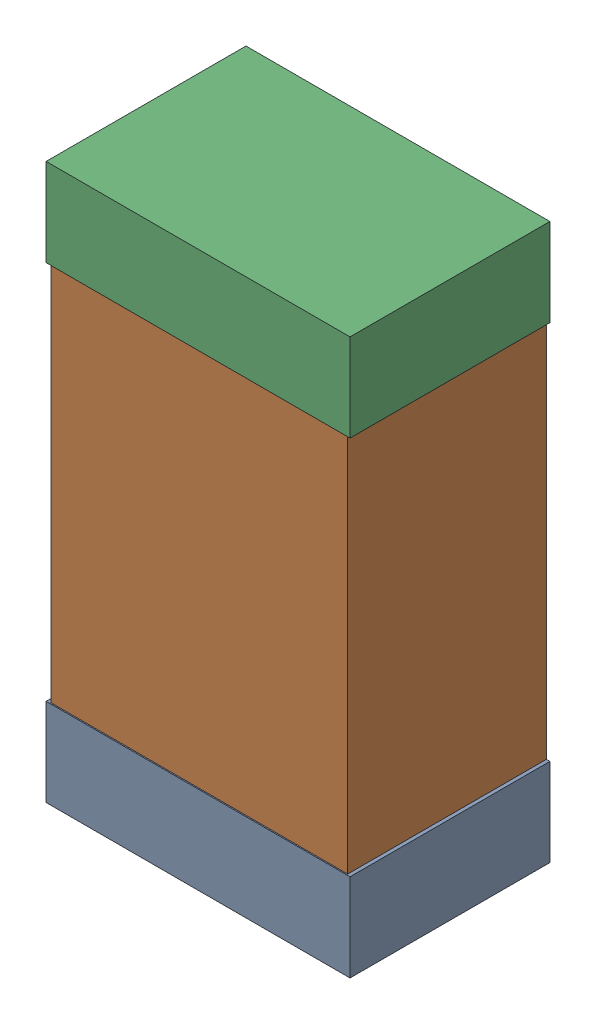
SolidWorks assembly R6Kanaloa_v2.0.0_Power, configuration Default. Lengths in mm.
Overall size (1.3 2.38 0.85).
6 component instances, 2 part files, 0 mates.
Components (placement in the parent):
- 330415056-1: 330415056 [Default] at (56.3 96.875 0) size (1.3 0.38 0.85)
  - Extruded_2-1: Extruded_2 [Default] at origin size (1.3 0.38 0.85)
- 352877008-1: 352877008 [Default] at (56.3 97.875 0) size (1.27 2.2 0.85)
  - Extruded_3-1: Extruded_3 [Default] at origin size (1.27 2.2 0.85)
- 330415056-2: 330415056 [Default] at (56.3 98.875 0) size (1.3 0.38 0.85)
  - Extruded_2-1: Extruded_2 [Default] at origin size (1.3 0.38 0.85)
